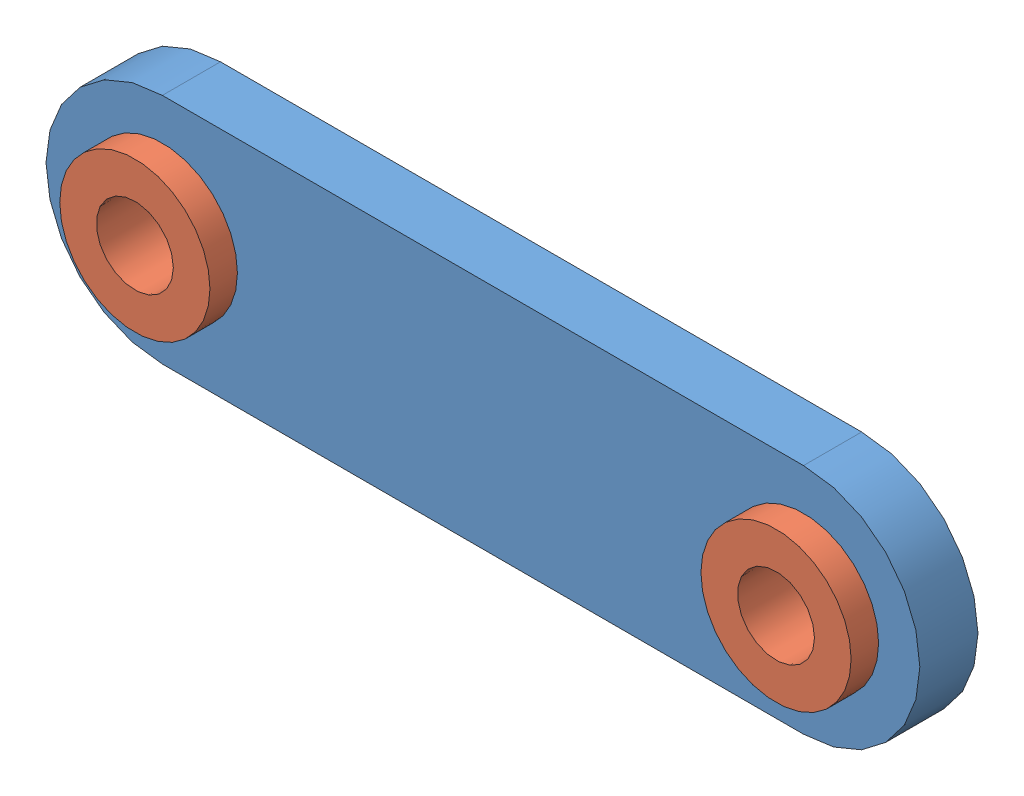
SolidWorks assembly Link arm assy (Fowrad), configuration Default. Lengths in mm.
Overall size (47.7 12.7 4.68).
3 component instances, 2 part files, 4 mates.
Components (placement in the parent):
- Link arm-1: Link arm [35mm] at origin size (47.7 12.7 3.17)
- M4 Bearing-1: M4 Bearing [Default] at (0 0 1.5) size (8.2 8.2 4.5)
- M4 Bearing-2: M4 Bearing [Default] at (35 0 1.5) size (8.2 8.2 4.5)
Mates (geometry in assembly coordinates):
- Concentric1: concentric aligned: cylinder of Link arm-1 through (0 0 -3.175) axis (0 0 1) radius 3; cylinder of M4 Bearing-1 through (0 0 9.5305) axis (0 0 1) radius 3
- Coincident1: coincident anti-aligned: plane of Link arm-1 through (35 0 0) normal (0 0 1); plane of M4 Bearing-1 through (0 4.1 0) normal (0 0 -1)
- Concentric2: concentric aligned: cylinder of Link arm-1 through (35 0 -3.175) axis (0 0 1) radius 3; cylinder of M4 Bearing-2 through (35 0 9.5305) axis (0 0 1) radius 3
- Coincident2: coincident anti-aligned: plane of Link arm-1 through (35 0 0) normal (0 0 1); plane of M4 Bearing-2 through (35 4.1 0) normal (0 0 -1)
